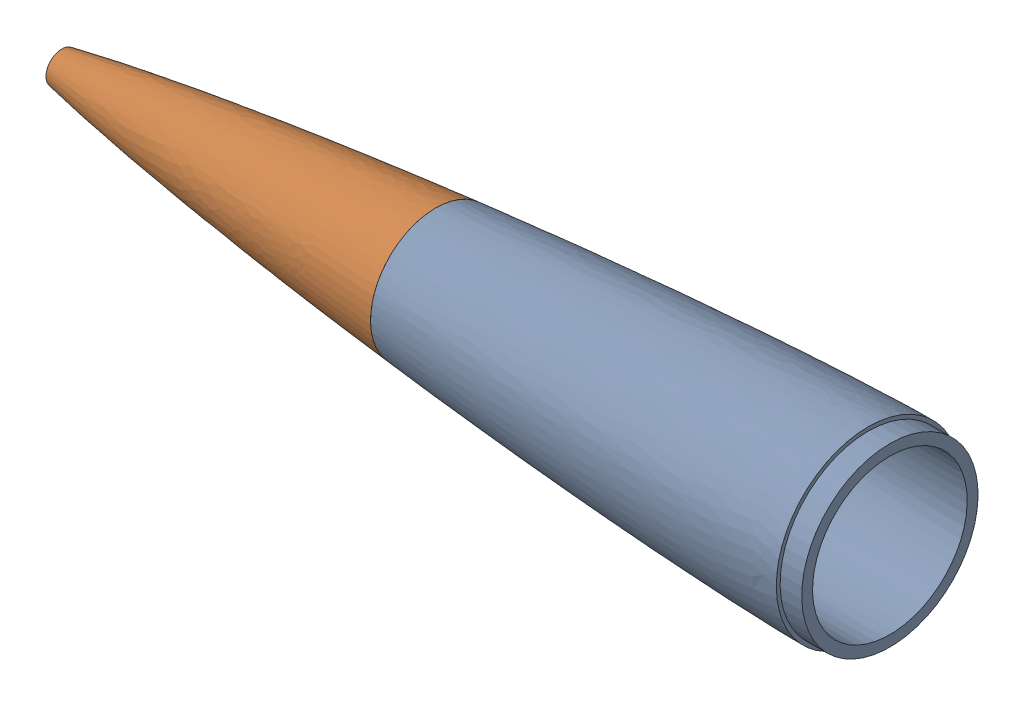
SolidWorks assembly Nose Cone Assm, configuration Default. Lengths in mm.
Overall size (382.8 85 85).
2 component instances, 2 part files, 3 mates.
Components (placement in the parent):
- Nose Cone bottom-1: Nose Cone bottom [Default] at origin size (210 85 85)
- Nose Cone Top-1: Nose Cone Top [Default] x (1 0 0) z (0 -0.849357 0.527818) size (187.8 60.1 60.1)
Mates (geometry in assembly coordinates):
- Coincident1: coordinate: point of Nose Cone bottom-1
- Concentric1: concentric aligned: circle of Nose Cone bottom-1; circle of Nose Cone Top-1
- Coincident3: coincident anti-aligned: plane of Nose Cone bottom-1 through (-210 0 0) normal (-1 0 0); plane of Nose Cone Top-1 through (-210 0 0) normal (1 0 0)
